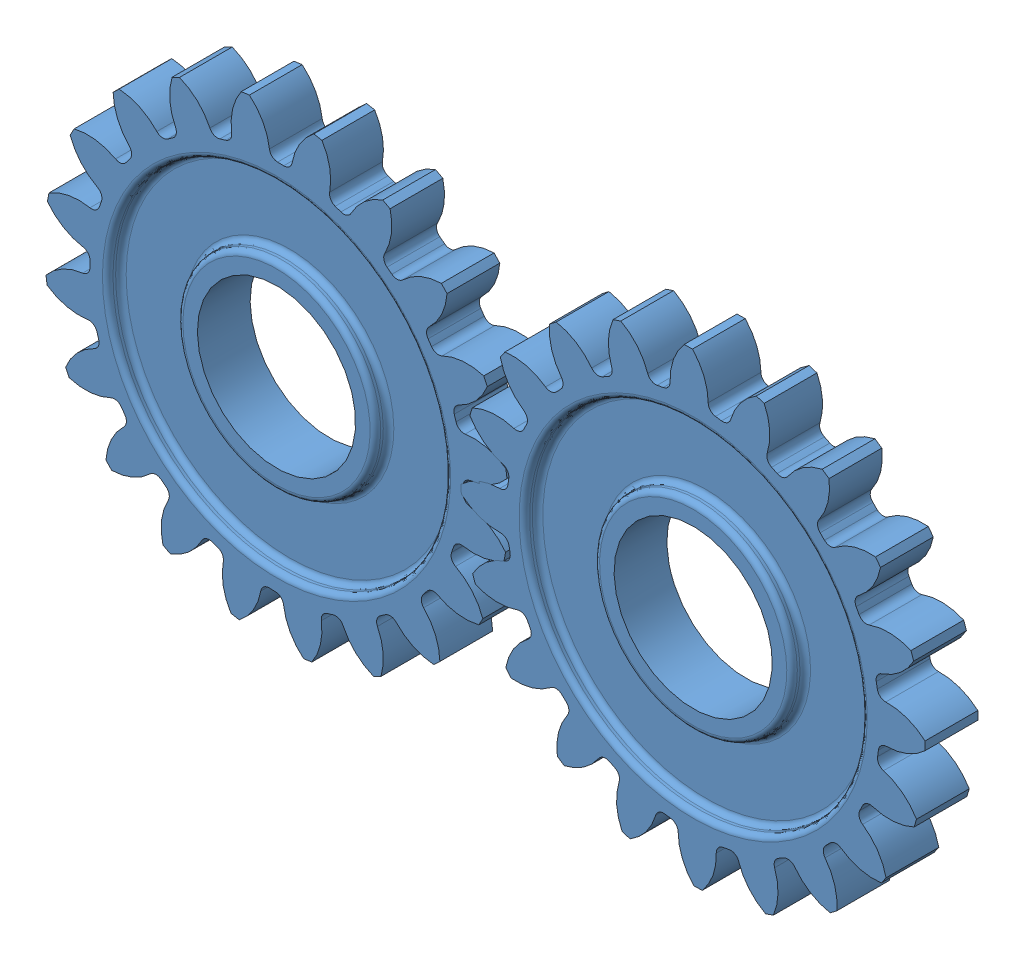
SolidWorks assembly gear test, configuration Default. Lengths in mm.
Overall size (97.31 59.59 5).
2 component instances, 1 part files, 5 mates.
Components (placement in the parent):
- GEAR_SAMPLE_SHEET_3-1: GEAR_SAMPLE_SHEET_3 [Default] at (-19.75 0 0) x (0.88067 -0.47373 0) z (0 0 1) size (44 44 5)
- GEAR_SAMPLE_SHEET_3-2: GEAR_SAMPLE_SHEET_3 [Default] at (19.75 0 0) x (0.944394 0.328815 0) z (0 0 1) size (44 44 5)
Mates (geometry in assembly coordinates):
- Concentric1: concentric: cylinder of GEAR_SAMPLE_SHEET_3-1 through (-19.75 0 -15) axis (0 0 1) radius 7.5
- Concentric3: concentric: cylinder of GEAR_SAMPLE_SHEET_3-2 through (19.75 0 -15) axis (0 0 1) radius 7.5
- Coincident3: coincident anti-aligned: plane of GEAR_SAMPLE_SHEET_3-1 through (-11.4965 16.3709 0) normal (0 0 -1)
- Coincident4: coincident anti-aligned: plane of GEAR_SAMPLE_SHEET_3-2 through (13.2641 17.1481 0) normal (0 0 -1)
- GearMate1: gear = 15 : 15 mm: cylinder of GEAR_SAMPLE_SHEET_3-1 through (-19.75 0 -15) axis (0 0 1) radius 7.5; cylinder of GEAR_SAMPLE_SHEET_3-2 through (19.75 0 -15) axis (0 0 1) radius 7.5
